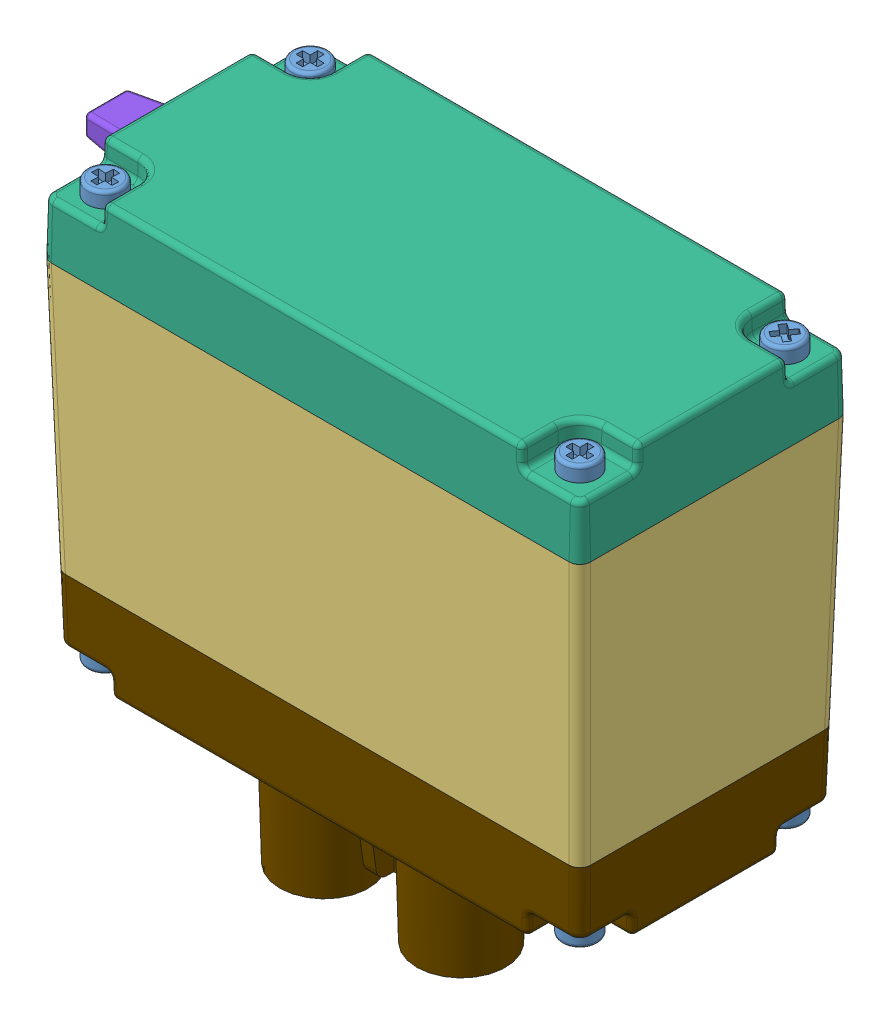
SolidWorks assembly 393, configuration Default. Lengths in mm.
Overall size (56.4 55.81 25).
28 component instances, 19 part files, 3 mates.
Components (placement in the parent):
- SPPM206-0150BO-1: SPPM206-0150BO [Default] at (-10.5 -23.5 9.5) x (-1 0 0) z (0 0 1) size (3.3 16.36 3.3)
- SPPM206-0150BO-2: SPPM206-0150BO [Default] at (-10.5 -23.5 -9.5) x (-1 0 0) z (0 0 1) size (3.3 16.36 3.3)
- SPPM204-0050BO-1: SPPM204-0050BO [Default] at (0 -6.45 -6.2) size (3.3 6.41 3.3)
- 276-2177-002 Rev1-1: 276-2177-002 Rev1 [Default] at origin size (50 27.05 25)
- SPPM206-0150BO-3: SPPM206-0150BO [Default] at (33.5 -23.5 -9.5) x (-1 0 0) z (0 0 1) size (3.3 16.36 3.3)
- 276-2177-008 Rev1-1: 276-2177-008 Rev1 [Default] at (25.7 -19.25 0) x (-0.086075 0 -0.996289) z (0 -1 0) size (16.7 16.7 17.5)
- 276-2177-010 Rev1-1: 276-2177-010 Rev1 [Default] at (24.2 -4.9 0) x (0 1 0) z (0.653198 0 -0.757187) size (20.8 2 2)
- 276-2177-001 Rev1-1: 276-2177-001 Rev1 [Default] at origin size (50 7.01 25)
- 276-2177-012 Rev1-1: 276-2177-012 Rev1 [Default] at (25.7 -19.1 0) x (-0.525336 0 0.850895) z (0 1 0) size (6 6 2.85)
- 276-2177-018 Rev1-1: 276-2177-018 Rev1 [Default] at (-12 2.1 0) x (0 0 -1) z (1 0 0) size (6.82 4.47 8.9)
- 276-2177-014 Rev1-1: 276-2177-014 Rev1 [Default] at (-11.6 -15 0) x (0 1 0) z (0 0 1) size (1 18.4 20.4)
- 276-2177-019 Rev1-1: 276-2177-019 Rev1 [Default] at (0.3 -33 0) x (-0.999228 0 0.03928) z (0.03928 0 0.999228) size (6.3 15.8 6.3)
- SPPM206-0150BO-4: SPPM206-0150BO [Default] at (33.5 -2.5 -9.5) x (-0.585444 0 0.810713) z (-0.810713 0 -0.585444) size (3.3 16.36 3.3)
- 276-2177-004 Rev1-1: 276-2177-004 Rev1 [Default] at (0 2.3 0) x (-0.521464 0 -0.853273) z (0 -1 0) size (5.83 5.83 4.5)
- SPPM206-0150BO-5: SPPM206-0150BO [Default] at (33.5 -2.5 9.5) size (3.3 16.36 3.3)
- 276-2177-019 Rev1-2: 276-2177-019 Rev1 [Default] at (13 -33 0) x (0.158525 0 -0.987355) z (-0.987355 0 -0.158525) size (6.3 15.8 6.3)
- SPPM204-0050BO-2: SPPM204-0050BO [Default] at (0 -6.45 6.2) size (3.3 6.41 3.3)
- FS130-FT-21100-1: FS130-FT-21100 [Default] at (0 -15 0) x (0 0 -1) z (0 1 0) size (20.4 15.4 34.7)
- 276-2177-006 Rev1-1: 276-2177-006 Rev1 [Default] at (24.2 -0.95 0) x (-0.999044 0 -0.043716) z (0 -1 0) size (20.25 20.26 13)
- 276-2177-009 Rev1-1: 276-2177-009 Rev1 [Default] at (15.1 -17.75 0) x (1 0 0) z (0 -1 0) size (2 2 27.5)
- 276-2177-011 Rev1-1: 276-2177-011 Rev1 [Default] at (12.1 -0.9 0) x (0 1 0) z (-0.101873 0 0.994797) size (14.8 2 2)
- 276-2177-007 Rev1_276-2177-007a-1: 276-2177-007 Rev1_276-2177-007a [Default] at (15.1 -10.55 0) x (0.26937 0 -0.963037) z (0 -1 0) size (14.01 14.03 13)
- 276-2177-013 Rev1-1: 276-2177-013 Rev1 [Default] at (25.7 -31.5 0) x (-1 0 0) z (0 1 0) size (10 10 10.05)
- SPPM206-0150BO-6: SPPM206-0150BO [Default] at (-10.5 -2.5 9.5) x (0.055695 0 -0.998448) z (0.998448 0 0.055695) size (3.3 16.36 3.3)
- 276-2177-003 Rev1-1: 276-2177-003 Rev1 [Default] at (0 -25 0) size (48.69 26 23.69)
- SPPM206-0150BO-7: SPPM206-0150BO [Default] at (-10.5 -2.5 -9.5) size (3.3 16.36 3.3)
- 276-2177-005 Rev1-1: 276-2177-005 Rev1 [Default] at (12.1 2.15 0) x (-0.981818 0 0.189823) z (0 -1 0) size (19.95 19.95 7)
- SPPM206-0150BO-8: SPPM206-0150BO [Default] at (33.5 -23.5 9.5) x (-1 0 0) z (0 0 1) size (3.3 16.36 3.3)
Mates (geometry in assembly coordinates):
- Distance1: distance = 0 mm aligned: plane of 276-2177-003 Rev1-1 through (-14.5022 -25 11.8454) normal (0 -0.026177 0.999657); plane of 276-2177-002 Rev1-1 through (-15.2348 0 12.5) normal (0 -0.026177 0.999657)
- Distance2: distance = 0 mm anti-aligned: plane of 276-2177-003 Rev1-1 through (0 -25 0) normal (0 1 0); plane of 276-2177-002 Rev1-1 through (0 -25 0) normal (0 -1 0)
- Coincident3: coincident aligned: plane of 276-2177-002 Rev1-1 through (36.5 0 14.2348) normal (0.999657 -0.026177 0); plane of 276-2177-003 Rev1-1 through (35.8454 -25 13.5022) normal (0.999657 -0.026177 0)
